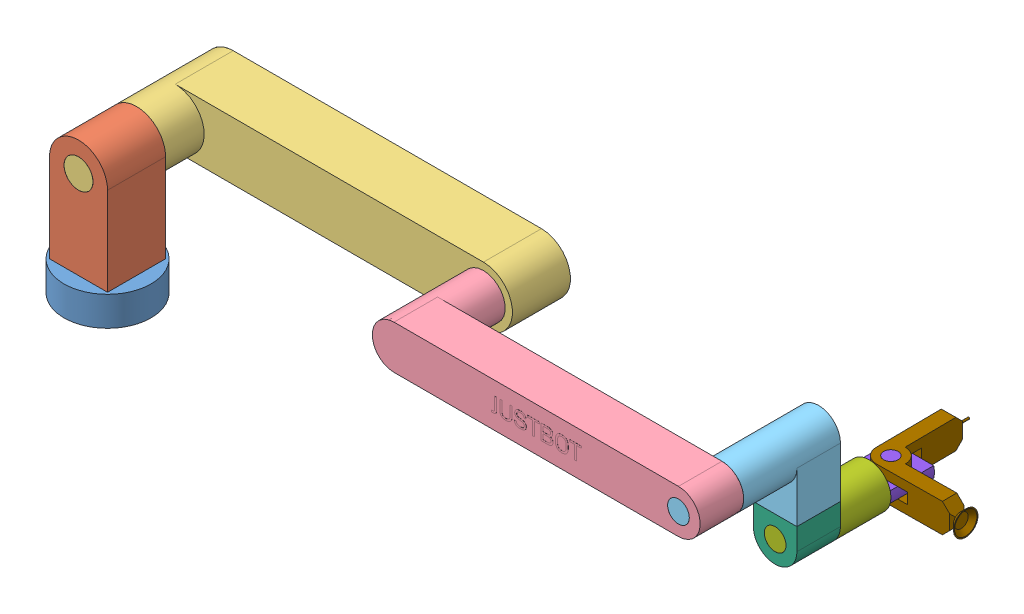
SolidWorks assembly assembly, configuration Default. Lengths in mm.
Overall size (989.52 202.5 442.44).
10 component instances, 9 part files, 24 mates.
Components (placement in the parent):
- link_0-1: link_0 [Default] at origin size (120 80.62 120)
- link_1-1: link_1 [Default] at (0 20.3125 0) x (-1 0 0) z (0 0 -1) size (80 161.88 80)
- link_2-1: link_2 [Default] at (0 142.1875 0) x (0 1 0) z (0 0 -1) size (80 505 213.4)
- link_3-1: link_3 [Default] at (425 142.1875 -133.3) x (0 1 0) z (0 0 -1) size (60 452.2 203.4)
- link_4-1: link_4 [Default] at (817.2 142.1875 0) x (1 0 0) z (0 0 -1) size (60 99.7 193.3)
- link_5-1: link_5 [Default] at (817.2 42.4875 -133.3) x (1 0 0) z (0 0 -1) size (60 90 60)
- link_6-1: link_6 [Default] at (817.2 42.4875 -133.3) x (0 1 0) z (0 0 -1) size (60 60 129.6)
- tool_assembly-2: tool_assembly [Default] at (817.2 42.4875 -232.901) x (0 1 0) z (0 0 -1) size (40 142.32 149.54)
  - tool_base-1: tool_base [Default] at origin size (40 60 60)
  - tool_tip-1: tool_tip [Default] at (0 0 30) x (1 0 0) z (0 -0.009356 0.999956) size (40 132.07 145.57)
Mates (geometry in assembly coordinates):
- Coincident3: coordinate: unknown of link_0-1
- Concentric1: concentric aligned: cylinder of link_0-1 through (0 60.3125 0) axis (0 -1 0) radius 20; cylinder of link_1-1 through (0 60.3125 0) axis (0 -1 0) radius 20
- Coincident4: coincident anti-aligned: plane of link_0-1 through (0 60.3125 0) normal (0 1 0); plane of link_1-1 through (0 60.3125 0) normal (0 -1 0)
- Concentric2: concentric aligned: cylinder of link_1-1 through (0 142.1875 -40) axis (0 0 1) radius 20; cylinder of link_2-1 through (0 142.1875 -40) axis (0 0 1) radius 20
- Coincident5: coincident anti-aligned: plane of link_1-1 through (0 142.1875 -40) normal (0 0 -1); plane of link_2-1 through (0 142.1875 -40) normal (0 0 1)
- Concentric3: concentric aligned: cylinder of link_2-1 through (425 142.1875 -173.3) axis (0 0 1) radius 20; cylinder of link_3-1 through (425 142.1875 -173.3) axis (0 0 1) radius 20
- Coincident6: coincident anti-aligned: plane of link_2-1 through (0 142.1875 -93.3) normal (0 0 1); plane of link_3-1 through (425 142.1875 -93.3) normal (0 0 -1)
- Concentric4: concentric anti-aligned: cylinder of link_3-1 through (817.2 142.1875 30) axis (0 0 -1) radius 15; cylinder of link_4-1 through (817.2 142.1875 -30) axis (0 0 1) radius 15
- Coincident7: coincident anti-aligned: plane of link_3-1 through (425 142.1875 -30) normal (0 0 -1); plane of link_4-1 through (817.2 142.1875 -30) normal (0 0 1)
- Concentric5: concentric aligned: cylinder of link_4-1 through (817.2 102.4875 -133.3) axis (0 -1 0) radius 15; cylinder of link_5-1 through (817.2 102.4875 -133.3) axis (0 -1 0) radius 15
- Coincident8: coincident anti-aligned: plane of link_4-1 through (787.2 72.4875 -163.3) normal (0 -1 0); plane of link_5-1 through (787.2 72.4875 -163.3) normal (0 1 0)
- Concentric6: concentric aligned: cylinder of link_5-1 through (817.2 42.4875 -163.3) axis (0 0 1) radius 15; cylinder of link_6-1 through (817.2 42.4875 -163.3) axis (0 0 1) radius 15
- Coincident9: coincident anti-aligned: plane of link_5-1 through (817.2 42.4875 -163.3) normal (0 0 -1); plane of link_6-1 through (817.2 42.4875 -163.3) normal (0 0 1)
- Coincident20: coincident anti-aligned: plane of link_6-1 through (817.2 42.4875 -232.901) normal (0 0 -1); plane of tool_assembly-2/tool_base-1 through (817.2 42.4875 -232.901) normal (0 0 1)
- Coincident21: coincident aligned: circle of link_6-1; circle of tool_assembly-2/tool_base-1
- Coincident22: coincident aligned: line of link_6-1 through (846.2474 34.9875 -232.901) axis (-1 0 0); line of tool_assembly-2/tool_base-1 through (846.2474 34.9875 -232.901) axis (-1 0 0)
- Parallel1: parallel aligned: plane of link_0-1 through (0 -20.3125 0) normal (0 -1 0); plane of link_2-1 through (0 102.1875 -173.3) normal (0 -1 0)
- Parallel2: parallel aligned: unknown of link_2-1; plane of link_3-1 through (425 112.1875 30) normal (0 -1 0)
- Parallel10: parallel aligned: plane of link_4-1 through (847.2 142.1875 -163.3) normal (1 0 0); plane of link_5-1 through (847.2 42.4875 -163.3) normal (1 0 0)
- Perpendicular1: perpendicular: plane of link_4-1 through (847.2 142.1875 -163.3) normal (1 0 0); plane of tool_assembly-2/tool_tip-1 through (817.2 22.4875 -262.901) normal (0 -1 0)
- Parallel12: parallel anti-aligned: plane of link_4-1 through (787.2 142.1875 -163.3) normal (-1 0 0)
- Coincident23: coincident aligned: plane of link_1-1 through (-40 20.3125 -40) normal (-1 0 0); unknown of link_2-1
- Parallel13: parallel aligned: unknown of link_2-1; unknown of link_3-1
- Parallel15: parallel aligned: unknown of link_3-1; unknown of link_4-1
